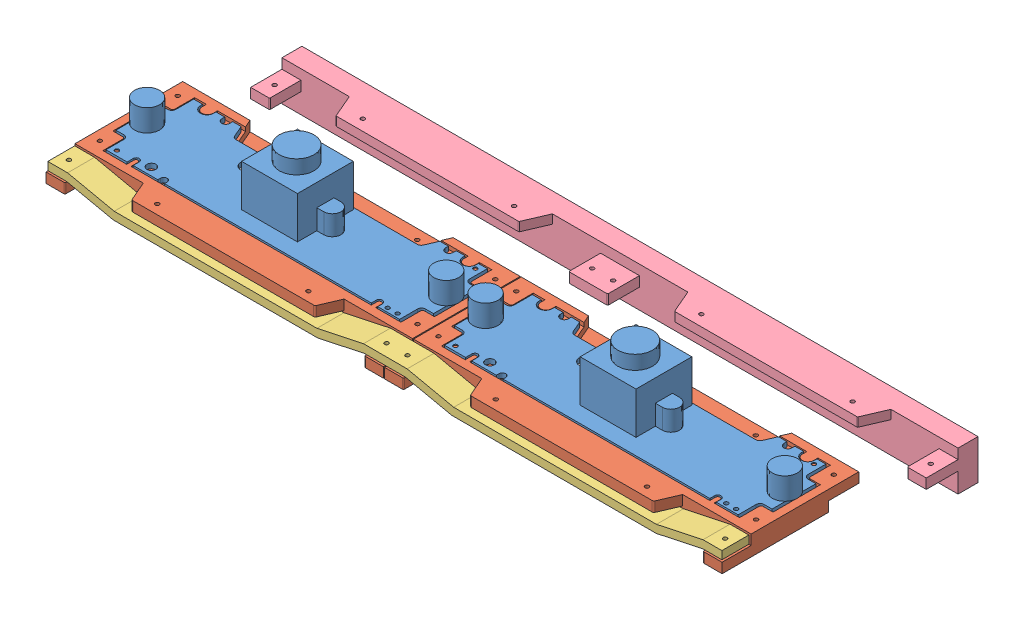
SolidWorks assembly Assembly_side_stacked, configuration Default. Lengths in mm.
Overall size (176.87 24.06 56.72).
6 component instances, 4 part files, 24 mates.
Components (placement in the parent):
- logitech_camera-1: logitech_camera [Default] at origin size (81.3 15.2 22)
- Mount-1: Mount [Default] at (-2.9697 -4 2.0884) size (84.6 5 34.26)
- side_stack_bottom_beugel-1: side_stack_bottom_beugel [Default] at (0.0305 -1.5 13.6049) x (1 0 -0.000002) z (0.000002 0 1) size (168.94 4.5 6.75)
- Mount-3: Mount [Default] at (81.8803 -4 2.0884) size (84.6 5 34.26)
- logitech_camera-2: logitech_camera [Default] at (84.85 0 0) size (81.3 15.2 22)
- side_stack_top_beugel-1: side_stack_top_beugel [Default] at (4.4471 1.1367 -14.7697) x (1 0 0) z (0 1 0) size (169.45 12.97 10)
Mates (geometry in assembly coordinates):
- Concentric1: concentric anti-aligned: cylinder of logitech_camera-1 through (-27.4 1.2 9) axis (0 -1 0) radius 1.125; cylinder of Mount-1 through (-27.4 -4 9) axis (0 1 0) radius 0.5
- Concentric7: concentric anti-aligned: cylinder of logitech_camera-1 through (-28.0168 1.2 -10.25) axis (0 -1 0) radius 1; cylinder of Mount-1 through (-28.0168 -4 -10.25) axis (0 1 0) radius 0.5
- Concentric6: concentric anti-aligned: cylinder of logitech_camera-1 through (28.0168 1.2 -10.25) axis (0 -1 0) radius 1; cylinder of Mount-1 through (28.0168 -4 -10.25) axis (0 1 0) radius 0.5
- Coincident3: coincident anti-aligned: plane of logitech_camera-1 through (37.8 0 6.5) normal (0 -1 0); plane of Mount-1 through (-2.9697 0 2.0884) normal (0 1 0)
- Concentric14: concentric anti-aligned: cylinder of Mount-3 through (57.45 -4 9) axis (0 1 0) radius 0.5; cylinder of logitech_camera-2 through (57.45 1.2 9) axis (0 -1 0) radius 1.125
- Concentric15: concentric anti-aligned: cylinder of Mount-3 through (56.8332 -4 -10.25) axis (0 1 0) radius 0.5; cylinder of logitech_camera-2 through (56.8332 1.2 -10.25) axis (0 -1 0) radius 1
- Concentric16: concentric anti-aligned: cylinder of Mount-3 through (112.8668 -4 -10.25) axis (0 1 0) radius 0.5; cylinder of logitech_camera-2 through (112.8668 1.2 -10.25) axis (0 -1 0) radius 1
- Coincident6: coincident anti-aligned: plane of Mount-3 through (81.8803 0 2.0884) normal (0 1 0); plane of logitech_camera-2 through (122.65 0 6.5) normal (0 -1 0)
- Coincident10: coincident aligned: plane of logitech_camera-1 through (0 0 0) normal (0 0 1); plane of assembly through (0 0 0) normal (0 0 1)
- Coincident11: coincident aligned: plane of logitech_camera-1 through (0 0 0) normal (0 1 0); plane of assembly through (0 0 0) normal (0 1 0)
- Coincident12: coincident aligned: plane of logitech_camera-1 through (0 0 0) normal (1 0 0); plane of assembly through (0 0 0) normal (1 0 0)
- Distance12: distance = 0.25 mm anti-aligned: plane of Mount-3 through (81.8803 -1.5 2.0884) normal (0 1 0); plane of side_stack_bottom_beugel-1 through (126.924 -1.25 20.3547) normal (0 -1 0)
- Distance13: distance = 0.25 mm anti-aligned: plane of Mount-3 through (42.6436 1 13.3547) normal (-1 0 0); plane of Mount-1 through (42.3936 1 13.3547) normal (1 0 0)
- Concentric24: concentric aligned: cylinder of side_stack_bottom_beugel-1 through (124.7436 -3.75 17.3652) axis (0 1 0) radius 0.5; cylinder of Mount-3 through (124.7436 -4 17.3652) axis (0 1 0) radius 0.5
- Concentric25: concentric aligned: cylinder of side_stack_bottom_beugel-1 through (103.9195 -3.75 16.1194) axis (0 1 0) radius 0.5; cylinder of Mount-3 through (103.9195 -4 16.1194) axis (0 1 0) radius 0.5
- Parallel6: parallel aligned: cylinder of Mount-1 through (-39.7064 -4 17.3652) axis (0 1 0) radius 0.5; cylinder of side_stack_bottom_beugel-1 through (-39.7064 -3.75 17.3655) axis (0 1 0) radius 0.5
- Parallel7: parallel aligned: cylinder of Mount-1 through (-18.8259 -4 16.1194) axis (0 1 0) radius 0.5; cylinder of side_stack_bottom_beugel-1 through (-18.8259 -3.75 16.1197) axis (0 1 0) radius 0.5
- Parallel8: parallel aligned: cylinder of Mount-1 through (19.0695 -4 16.1194) axis (0 1 0) radius 0.5; cylinder of side_stack_bottom_beugel-1 through (19.0695 -3.75 16.1196) axis (0 1 0) radius 0.5
- Parallel9: parallel aligned: cylinder of Mount-1 through (39.8936 -4 17.3652) axis (0 1 0) radius 0.5; cylinder of side_stack_bottom_beugel-1 through (39.8936 -3.75 17.3653) axis (0 1 0) radius 0.5
- Distance19: distance = 0.25 mm anti-aligned: plane of side_stack_top_beugel-1 through (-15.9406 -1.375 7.6469) normal (-0.919156 0 0.393893); plane of Mount-1 through (-16.1704 -1.5 7.7454) normal (0.919156 0 -0.393893)
- Distance20: distance = 0.25 mm anti-aligned: plane of side_stack_top_beugel-1 through (15.1949 -1.375 9.8939) normal (0.918766 0 0.394802); plane of Mount-1 through (15.4246 -1.5 9.9926) normal (-0.918766 0 -0.394802)
- Distance21: distance = 0.125 mm anti-aligned: plane of Mount-1 through (-2.9697 -1.5 2.0884) normal (0 1 0); plane of side_stack_top_beugel-1 through (-2.9697 -1.375 2.0884) normal (0 -1 0)
- Distance22: distance = 0.25 mm anti-aligned: plane of Mount-1 through (-2.9697 -1.5 2.0884) normal (0 1 0); plane of side_stack_bottom_beugel-1 through (-42.0195 -1.25 20.355) normal (0 -1 0)
- Coincident33: coincident aligned: plane of Mount-1 through (-42.2064 1 -13.6453) normal (0 0 -1); plane of Mount-3 through (42.6436 1 -13.6453) normal (0 0 -1)
